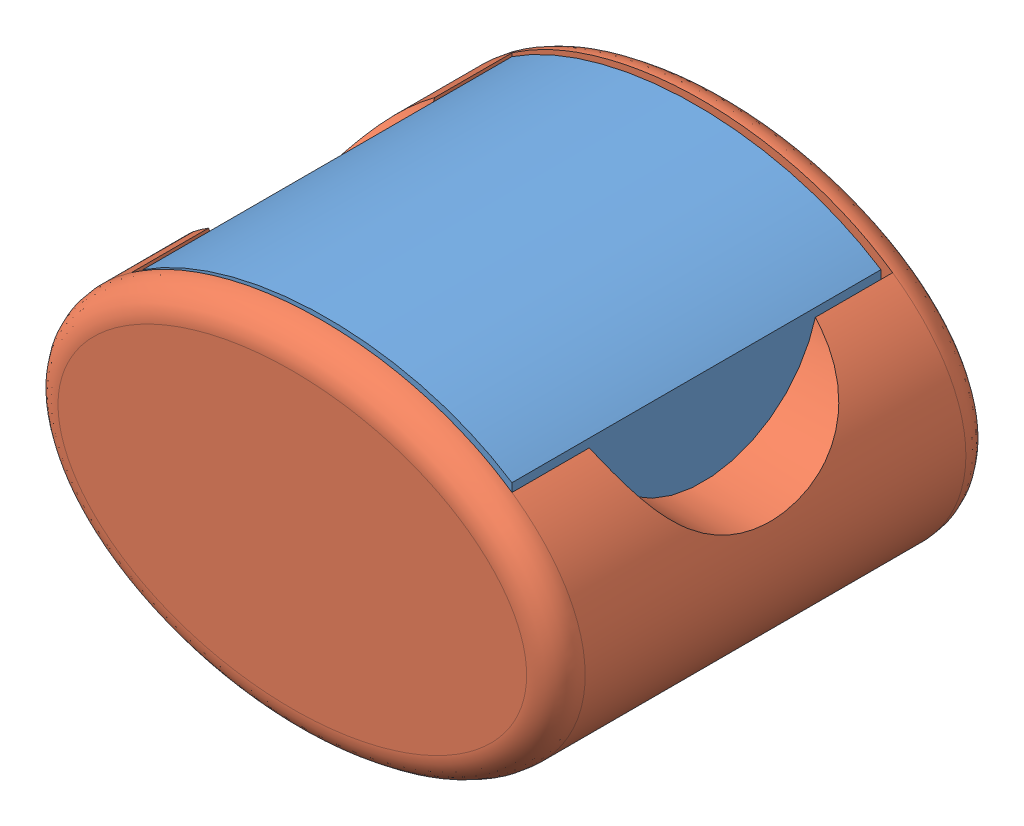
SolidWorks assembly Clip Assembly, configuration Default. Lengths in mm.
Overall size (49.71 34.45 38.1).
30 component instances, 11 part files, 6 mates.
Components (placement in the parent):
- Clip Top-1: Clip Top [Default] at (-94.5981 7.9826 21.7919) size (45.72 15.24 35.05)
- Clip Bottom-1: Clip Bottom [Default] at (-94.5981 8.0965 21.7919) size (49.71 34.45 38.1)
- Final Flashlight PCB-1: Final Flashlight PCB [Default] at (-108.5681 3.4722 24.9669) x (1 0 0) z (0 -1 0) size (32.07 34.43 17.34)
  - Board_1-1: Board_1 [Default] at origin size (27.94 31.75 0.41)
  - Imported_1-1: Imported_1 [Default] at origin size (27.76 30.96 17.34)
    - keystone-PN1025-7_1-1: keystone-PN1025-7_1 [Default] at (13.9955 14.1608 -2.9515) x (1 0 0) z (0 1 0) size (27.76 17.34 30.96)
  - U1_1-1: U1_1 [Default] at origin size (3.01 2.91 1.23)
    - SOT23-3_1-1: SOT23-3_1 [Default] at (13.9939 25.8873 0) x (0 -1 0) z (0 0 1) size (2.91 3.01 1.23)
    - 5808185472-1: 5808185472 [Default] at (14.097 26.162 0) size (0.25 0.25 0.25)
      - Extruded_1-1: Extruded_1 [Default] at origin size (0.25 0.25 0.25)
  - R3_1-1: R3_1 [Default] at origin size (0.95 1.7 0.9)
    - 5808185088-1: 5808185088 [Default] at (18.288 9.767 0) size (0.95 1.7 0.9)
      - Extruded_1_2-1: Extruded_1_2 [Default] at origin size (0.95 1.7 0.9)
  - R2_1-1: R2_1 [Default] at origin size (0.95 1.7 0.9)
    - 5808185088-1: 5808185088 [Default] at (16.129 9.767 0) size (0.95 1.7 0.9)
      - Extruded_1_2-1: Extruded_1_2 [Default] at origin size (0.95 1.7 0.9)
  - R1_1-1: R1_1 [Default] at origin size (0.95 1.7 0.9)
    - 5808185088-1: 5808185088 [Default] at (10.045 9.767 0) size (0.95 1.7 0.9)
      - Extruded_1_2-1: Extruded_1_2 [Default] at origin size (0.95 1.7 0.9)
  - R4_1-1: R4_1 [Default] at origin size (1.7 0.95 0.9)
    - 5808184896-1: 5808184896 [Default] at (18.046 12.827 0) size (1.7 0.95 0.9)
      - Extruded_1_3-1: Extruded_1_3 [Default] at origin size (1.7 0.95 0.9)
  - C2_1-1: C2_1 [Default] at origin size (0.95 1.75 1.3)
    - 5808185280-1: 5808185280 [Default] at (11.303 26.859 0) size (0.95 1.75 1.3)
      - Extruded_1_4-1: Extruded_1_4 [Default] at origin size (0.95 1.75 1.3)
  - C1_1-1: C1_1 [Default] at origin size (1.75 0.95 1.3)
    - 5808184704-1: 5808184704 [Default] at (13.843 22.795 0) size (1.75 0.95 1.3)
      - Extruded_1_5-1: Extruded_1_5 [Default] at origin size (1.75 0.95 1.3)
  - ATTiny85_1-1: ATTiny85_1 [Default] at origin size (8.25 5.36 2.16)
    - 8S2_1-1: 8S2_1 [Default] at (19.4181 20.066 0) x (0 1 0) z (0 0 1) size (8.25 5.36 2.16)
Mates (geometry in assembly coordinates):
- Distance1: distance = 0.508 mm anti-aligned: plane of Clip Top-1 through (-110.6001 25.2312 21.7919) normal (-1 0 0); plane of Clip Bottom-1 through (-111.1081 8.0965 57.3519) normal (1 0 0)
- Distance3: distance = 0.508 mm anti-aligned: plane of Clip Top-1 through (-94.5981 25.2312 56.8439) normal (0 0 1); plane of Clip Bottom-1 through (-94.5981 8.0965 57.3519) normal (0 0 -1)
- Parallel1: parallel anti-aligned: plane of Clip Bottom-1 through (-79.9931 -0.7935 24.3319) normal (0 1 0); plane of Final Flashlight PCB-1/Board_1-1 through (-108.5681 3.4722 56.7169) normal (0 -1 0)
- Parallel2: parallel anti-aligned: plane of Clip Bottom-1 through (-94.5981 8.0965 24.3319) normal (0 0 1); plane of Final Flashlight PCB-1/Board_1-1 through (-80.6281 3.8837 24.9669) normal (0 0 -1)
- Concentric1: concentric anti-aligned: circle of Clip Bottom-1; circle of Final Flashlight PCB-1/Board_1-1
- Coincident3: coincident: plane of Clip Bottom-1 through (-106.0281 -8.3013 54.1769) normal (0 1 0); plane of Final Flashlight PCB-1/Board_1-1 through (-108.5681 -8.3013 56.7169) normal (0 -1 0)
